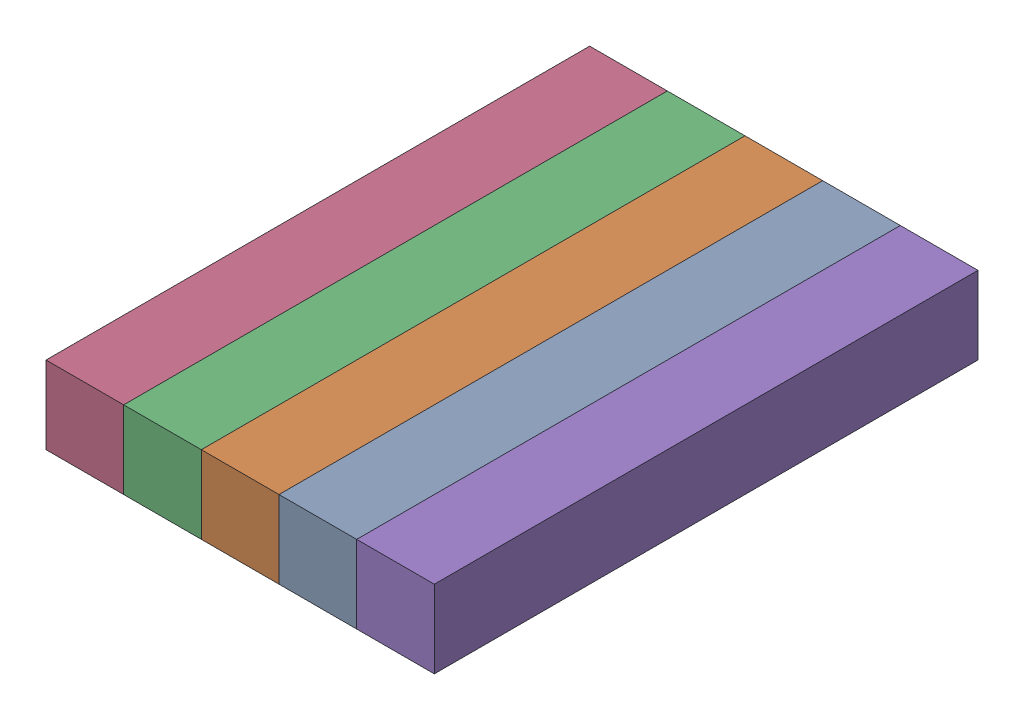
SolidWorks assembly Bottom, configuration Default. Lengths in mm.
Overall size (250 50 350).
5 component instances, 1 part files, 12 mates.
Components (placement in the parent):
- Lower-part-1: Lower-part [Default] at (-11.6531 84.0471 -50.9511) size (50 50 350)
- Lower-part-2: Lower-part [Default] at (-61.6531 84.0471 -50.9511) size (50 50 350)
- Lower-part-3: Lower-part [Default] at (-111.6531 84.0471 -50.9511) size (50 50 350)
- Lower-part-4: Lower-part [Default] at (-161.6531 84.0471 -50.9511) size (50 50 350)
- Lower-part-5: Lower-part [Default] at (38.3469 84.0471 -50.9511) size (50 50 350)
Mates (geometry in assembly coordinates):
- Coincident1: coincident anti-aligned: plane of Lower-part-3 through (-136.6531 59.0471 299.0489) normal (-1 0 0); plane of Lower-part-4 through (-136.6531 59.0471 299.0489) normal (1 0 0)
- Coincident2: coincident anti-aligned: plane of Lower-part-2 through (-86.6531 59.0471 299.0489) normal (-1 0 0); plane of Lower-part-3 through (-86.6531 59.0471 299.0489) normal (1 0 0)
- Coincident3: coincident anti-aligned: plane of Lower-part-1 through (-36.6531 59.0471 299.0489) normal (-1 0 0); plane of Lower-part-2 through (-36.6531 59.0471 299.0489) normal (1 0 0)
- Coincident4: coincident: plane of Lower-part-1 through (13.3469 59.0471 299.0489) normal (1 0 0); plane of Lower-part-5 through (13.3469 59.0471 299.0489) normal (-1 0 0)
- Coincident5: coincident aligned: plane of Lower-part-3 through (-86.6531 109.0471 299.0489) normal (0 1 0); plane of Lower-part-4 through (-136.6531 109.0471 299.0489) normal (0 1 0)
- Coincident6: coincident aligned: plane of Lower-part-2 through (-36.6531 109.0471 299.0489) normal (0 1 0); plane of Lower-part-3 through (-86.6531 109.0471 299.0489) normal (0 1 0)
- Coincident7: coincident aligned: plane of Lower-part-1 through (13.3469 109.0471 299.0489) normal (0 1 0); plane of Lower-part-2 through (-36.6531 109.0471 299.0489) normal (0 1 0)
- Coincident8: coincident: plane of Lower-part-1 through (13.3469 109.0471 299.0489) normal (0 1 0); plane of Lower-part-5 through (63.3469 109.0471 299.0489) normal (0 1 0)
- Coincident9: coincident aligned: plane of Lower-part-3 through (-111.6531 84.0471 299.0489) normal (0 0 1); plane of Lower-part-4 through (-161.6531 84.0471 299.0489) normal (0 0 1)
- Coincident10: coincident aligned: plane of Lower-part-2 through (-61.6531 84.0471 299.0489) normal (0 0 1); plane of Lower-part-3 through (-111.6531 84.0471 299.0489) normal (0 0 1)
- Coincident11: coincident aligned: plane of Lower-part-1 through (-11.6531 84.0471 299.0489) normal (0 0 1); plane of Lower-part-2 through (-61.6531 84.0471 299.0489) normal (0 0 1)
- Coincident12: coincident aligned: plane of Lower-part-1 through (-11.6531 84.0471 299.0489) normal (0 0 1); plane of Lower-part-5 through (38.3469 84.0471 299.0489) normal (0 0 1)
